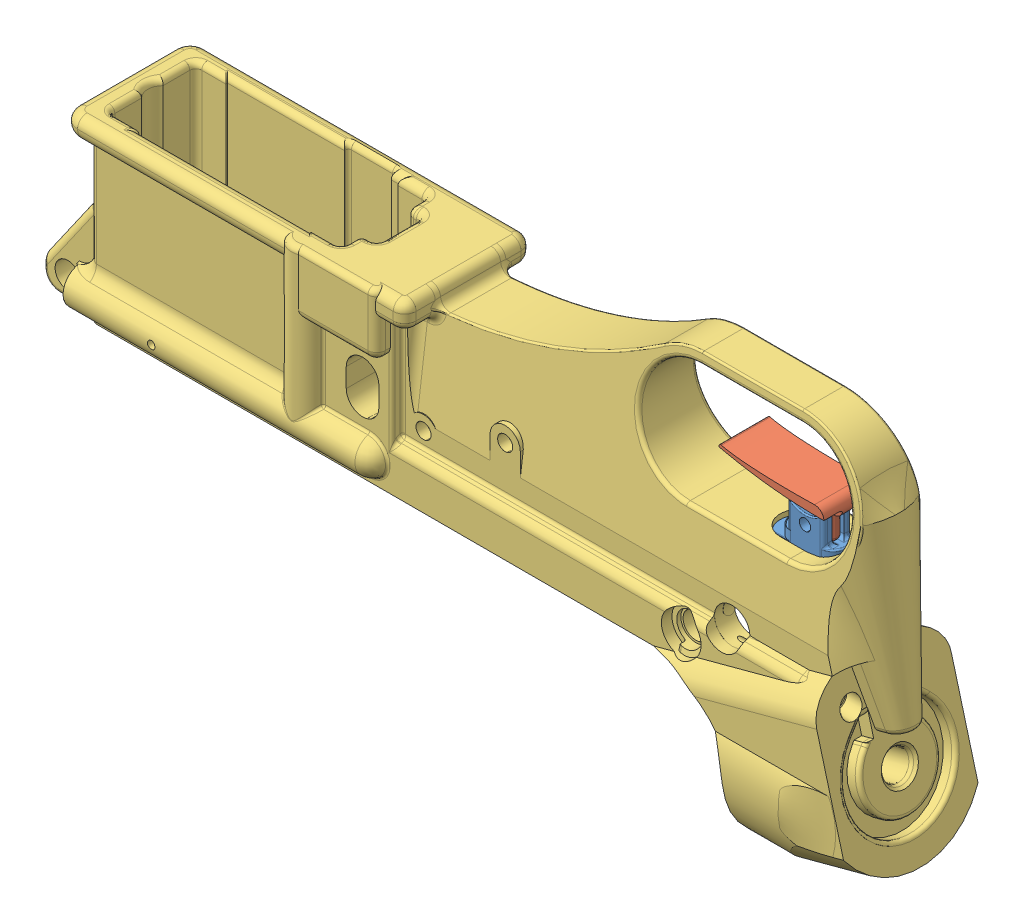
SolidWorks assembly trigger-assemble, configuration 默认. Lengths in mm.
Overall size (217.08 108.74 38.84).
3 component instances, 3 part files, 5 mates.
Components (placement in the parent):
- LongTrigger-Straight.step-1: LongTrigger-Straight.step [默认] at (-73.5263 4.4692 101.0056) size (101.01 24.9 16.87)
- trigger-1: trigger [默认] at (6.0677 10.3138 102.5556) x (-1 0 0) z (0 -1 0) size (27.59 12.8 13.2)
- MKIIb_Reciever-1: MKIIb_Reciever [默认] at (-110.0254 53.4705 71.5783) x (0 0 1) z (0.00009 -1 0) size (38.84 217.07 108.72)
Mates (geometry in assembly coordinates):
- Concentric1: concentric anti-aligned: cylinder of LongTrigger-Straight.step-1 through (-64.3391 -2.3891 109.4384) axis (0 0 -1) radius 1.9812; cylinder of MKIIb_Reciever-1 through (-64.3391 -2.3891 111.3876) axis (0 0 1) radius 1.9812
- Distance1: distance = 2 mm anti-aligned: plane of MKIIb_Reciever-1 through (-67.9466 5.4846 110.016) normal (0 0 -1); plane of LongTrigger-Straight.step-1 through (-64.3391 -2.3891 108.016) normal (0 0 1)
- Concentric2: concentric aligned: cylinder of LongTrigger-Straight.step-1 through (6.2518 10.3001 93.1886) axis (0 0 1) radius 1.5; cylinder of trigger-1 through (6.2518 10.3001 99.7556) axis (0 0 1) radius 1.5
- Coincident5: coincident anti-aligned: plane of LongTrigger-Straight.step-1 through (1.4737 7.0854 102.5556) normal (0 0 -1); plane of trigger-1 through (6.2518 20.88 102.5556) normal (0 0 1)
- Parallel1: parallel anti-aligned: plane of LongTrigger-Straight.step-1 through (11.7475 7.0854 88.3056) normal (0 1 0); plane of trigger-1 through (10.1152 7.0901 99.7556) normal (0 -1 0)
